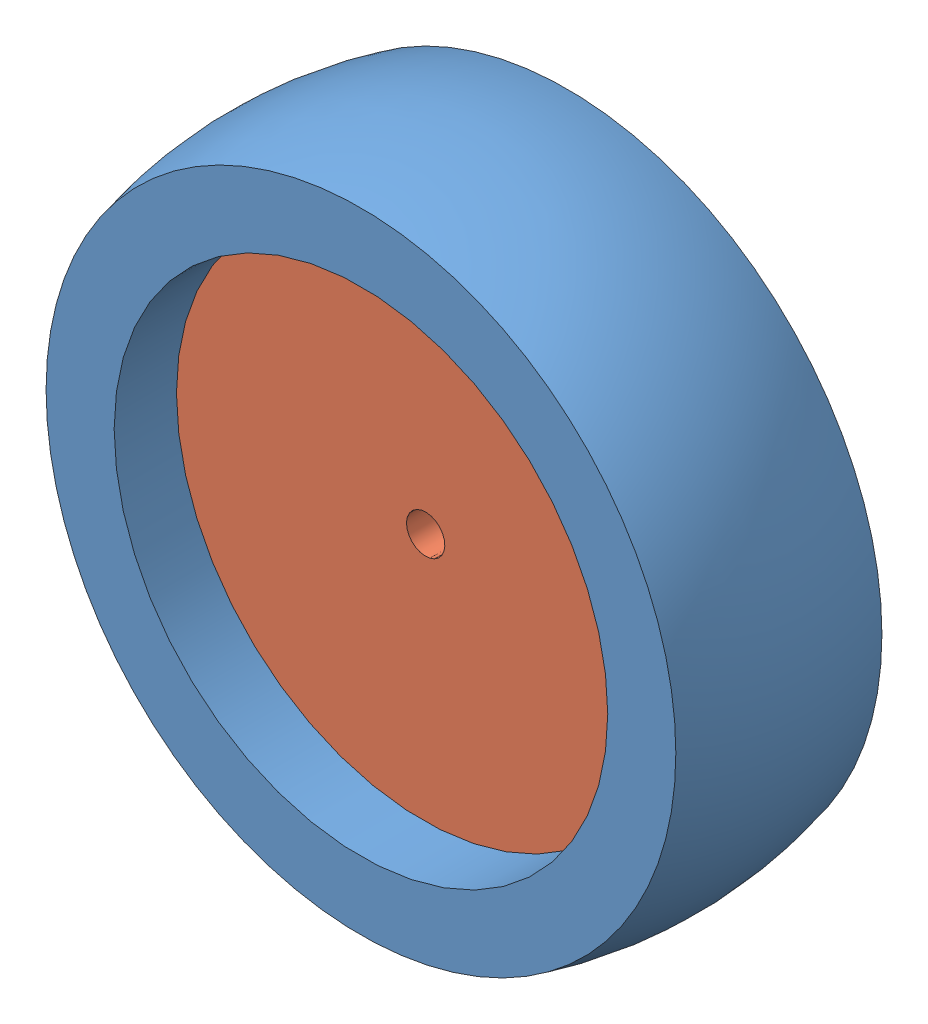
SolidWorks assembly makeblock_fat_wheel_asm, configuration Default. Lengths in mm.
Overall size (81.21 81.21 22.75).
2 component instances, 2 part files, 6 mates.
Components (placement in the parent):
- makeblock_fat_tire-1: makeblock_fat_tire [Default] at origin size (68.5 68.5 21.5)
- wheels-1: wheels [Mbot_fat] at (0 0 -4) x (-0.67387 0.73885 0) z (0 0 1) size (57.49 57.49 16)
Mates (geometry in assembly coordinates):
- InPlace1: in place: plane of makeblock_fat_tire-1 through (0 28.75 -4.25) normal (0 0 1); plane of ? through (0 0 -4.25) normal (0 0 1); moOrthogonalPlaneRef_w of makeblock_fat_tire-1 through (0 28.75 -4.25) normal (0 0 1); plane of ? through (0 0 -4.25) normal (0 1 0); plane of makeblock_fat_tire-1 through (0 28.75 -4.25) normal (0 0 1); plane of ? through (0 0 -4.25) normal (1 0 0); plane of makeblock_fat_tire-1 through (0 28.75 -4.25) normal (0 0 1); unknown of ?
- Coincident1: coincident aligned: plane of ?; plane of ?
- Coincident2: coincident aligned: moOrthogonalPlaneRef_w of makeblock_fat_tire-1 through (0 0 -4.25) normal (0 1 0); plane of makeblock_fat_wheel-1 through (0 0 -4.25) normal (0 1 0)
- Coincident3: coincident anti-aligned: moOrthogonalPlaneRef_w of makeblock_fat_tire-1 through (0 0 -4.25) normal (-1 0 0); plane of makeblock_fat_wheel-1 through (0 0 -4.25) normal (1 0 0)
- Concentric1: concentric anti-aligned: cylinder of makeblock_fat_tire-1 through (0 0 733.316) axis (0 0 1) radius 28.75; cylinder of wheels-1 through (0 0 4) axis (0 0 -1) radius 28.75
- Width1: width aligned: plane of wheels-1 through (0 0 -4) normal (0 0 -1); plane of makeblock_fat_tire-1 through (0 0 4) normal (0 0 1); plane of wheels-1 through (0 25.75 4.25) normal (0 0 -1); plane of makeblock_fat_tire-1 through (0 28.75 -4.25) normal (0 0 1)
